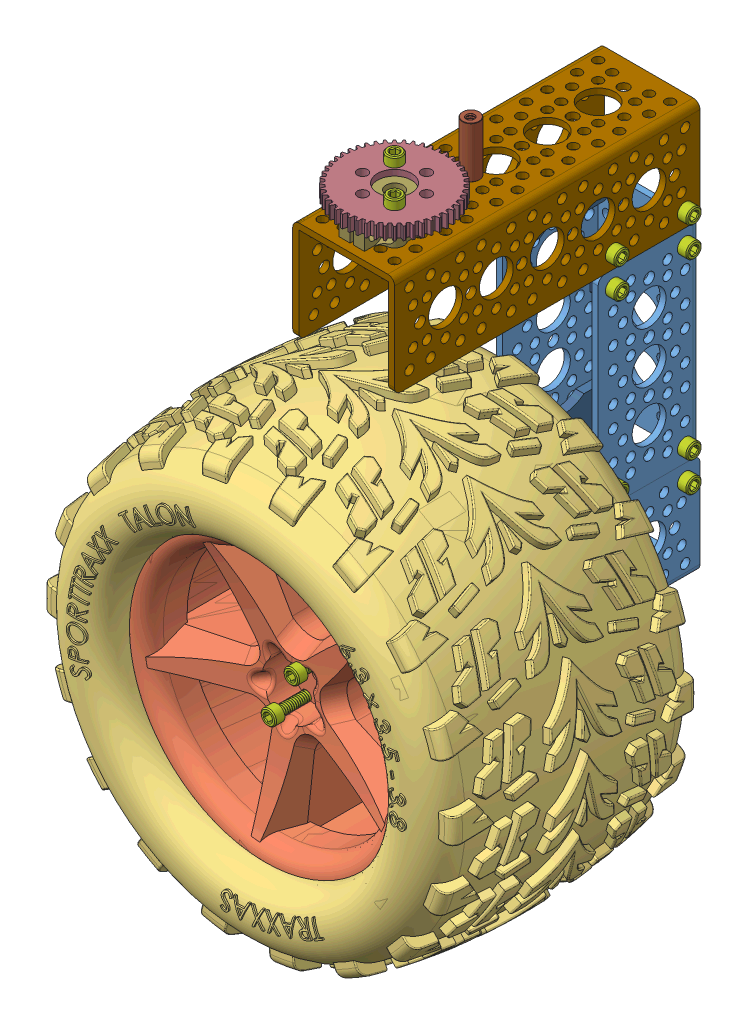
SolidWorks assembly Corner Wheel Assembly, configuration Default. Lengths in mm.
Overall size (182.86 244.12 157.75).
49 component instances, 13 part files, 84 mates.
Components (placement in the parent):
- Wheel Assembly-1: Wheel Assembly [Middle Wheel] at (53.3657 55.989 87.6081) size (182.86 183.23 157.75)
  - 3 Aluminum Channel-1: 3 Aluminum Channel [Default] at (-17.2943 26.284 30.6898) size (38.1 38.1 76.2)
  - Wheel-1: Wheel [Default] at (-70.1316 -42.318 140.7011) x (0 0 1) z (0.106642 0.994297 0) size (106.88 166.05 166.47)
    - Wheel Rim-1: Wheel Rim [Default] at (-5.7009 62.13 94.8184) size (78.74 101.6 101.6)
    - Wheel Tire-1: Wheel Tire [Default] at (-5.7009 62.1295 94.8183) size (106.88 166.05 166.47)
  - 25m Bore Side Tapped Clamping Mount-1: 25m Bore Side Tapped Clamping Mount [Default] at (1.1407 51.5007 106.1447) x (1 0 0) z (0 -1 0) size (33.76 11.43 64.42)
    - 25m Bore Side Tapped Clamping Mount-1: 25m Bore Side Tapped Clamping Mount [Default] at (0.615 -8.6446 6.1668) size (33.76 7.62 39.7)
    - #6-32 0_5 Bolt-1: #6-32 0_5 Bolt [Default] at (-31.135 -4.8346 -13.2719) x (0 0.2706 0.962692) z (-1 0 0) size (5.57 5.57 16.21)
  - 25mm Motor and Encoder-1: 25mm Motor and Encoder [Default] at (-28.8188 49.6309 104.1252) x (0.990268 -0.139173 0) z (0 0 1) size (25 32.85 80)
  - 6-32_SHCS-1: 6-32_SHCS [6-32 SHCS X .250] at (14.4557 58.8044 101.3102) x (0 0 -1) z (1 0 0) size (5.74 5.74 9.86)
  - 6-32_SHCS-2: 6-32_SHCS [6-32 SHCS X .250] at (-10.9443 58.8044 101.3102) x (0 0.924225 0.381849) z (-1 0 0) size (5.74 5.74 9.86)
  - 6-32_SHCS-3: 6-32_SHCS [6-32 SHCS X .250] at (-10.9443 31.8636 101.3102) x (0 0.924225 0.381849) z (-1 0 0) size (5.74 5.74 9.86)
  - 6-32_SHCS-4: 6-32_SHCS [6-32 SHCS X .250] at (14.4557 31.8636 101.3102) x (0 0 -1) z (1 0 0) size (5.74 5.74 9.86)
  - 6-32_SHCS-5: 6-32_SHCS [6-32 SHCS X 1.250] at (6.0479 54.1206 133.797) x (-0.106642 -0.994297 0) z (0 0 1) size (5.74 5.74 35.26)
  - 6-32_SHCS-6: 6-32_SHCS [6-32 SHCS X 1.250] at (-2.5366 36.5473 133.797) x (-0.106642 -0.994297 0) z (0 0 1) size (5.74 5.74 35.26)
  - 4mm Face Tapped Clamping Hub-1: 4mm Face Tapped Clamping Hub [Default] at (1.7557 45.334 125.4752) x (0.945719 0.324986 0) z (0.324986 -0.945719 0) size (20.57 9.64 26.29)
- 3 Aluminum Channel-1: 3 Aluminum Channel [Default] at (36.0714 196.573 118.2979) x (1 0 0) z (0 -1 0) size (38.1 38.1 76.2)
- 4.5 Aluminum channel-1: 4.5 Aluminum channel [Default] at (36.0714 234.673 232.5979) x (1 0 0) z (0 0 -1) size (38.1 38.1 114.3)
- Channel Connector-1: Channel Connector [Default] at (71.8854 120.373 137.3479) x (0 0 1) z (0 -1 0) size (33.29 3.38 17.51)
- Channel Connector-2: Channel Connector [Default] at (41.5324 120.373 137.3479) x (0 0 1) z (0 -1 0) size (33.29 3.38 17.51)
- Channel Connector-3: Channel Connector [Default] at (71.8854 196.573 137.3479) x (0 0 1) z (0 -1 0) size (33.29 3.38 17.51)
- Channel Connector-4: Channel Connector [Default] at (38.3574 196.573 137.3479) x (0 0 1) z (0 1 0) size (33.29 3.38 17.51)
- 6-32_SHCS-1: 6-32_SHCS [6-32 SHCS X .250] at (42.4214 114.7934 150.8183) x (0 0.924225 0.381849) z (-1 0 0) size (5.74 5.74 9.86)
- 6-32_SHCS-2: 6-32_SHCS [6-32 SHCS X .250] at (67.8214 114.7934 150.8183) x (0 0 -1) z (1 0 0) size (5.74 5.74 9.86)
- 6-32_SHCS-3: 6-32_SHCS [6-32 SHCS X .250] at (42.4214 114.7934 123.8776) x (0 0.924225 0.381849) z (-1 0 0) size (5.74 5.74 9.86)
- 6-32_SHCS-4: 6-32_SHCS [6-32 SHCS X .250] at (67.8214 114.7934 123.8776) x (0 0 -1) z (1 0 0) size (5.74 5.74 9.86)
- 6-32_SHCS-5: 6-32_SHCS [6-32 SHCS X .250] at (67.8214 125.9526 123.8776) x (0 -0.924225 -0.381849) z (1 0 0) size (5.74 5.74 9.86)
- 6-32_SHCS-6: 6-32_SHCS [6-32 SHCS X .250] at (42.4214 125.9526 123.8776) x (0 0 1) z (-1 0 0) size (5.74 5.74 9.86)
- 6-32_SHCS-7: 6-32_SHCS [6-32 SHCS X .250] at (42.4214 125.9526 150.8183) x (0 0.924225 0.381849) z (-1 0 0) size (5.74 5.74 9.86)
- 6-32_SHCS-8: 6-32_SHCS [6-32 SHCS X .250] at (67.8214 125.9526 150.8183) x (0 0 -1) z (1 0 0) size (5.74 5.74 9.86)
- 6-32_SHCS-9: 6-32_SHCS [6-32 SHCS X .250] at (42.4214 190.9934 150.8183) x (0 0.924225 0.381849) z (-1 0 0) size (5.74 5.74 9.86)
- 6-32_SHCS-10: 6-32_SHCS [6-32 SHCS X .250] at (67.8214 190.9934 150.8183) x (0 0 -1) z (1 0 0) size (5.74 5.74 9.86)
- 6-32_SHCS-11: 6-32_SHCS [6-32 SHCS X .250] at (42.4214 190.9934 123.8776) x (0 0.924225 0.381849) z (-1 0 0) size (5.74 5.74 9.86)
- 6-32_SHCS-12: 6-32_SHCS [6-32 SHCS X .250] at (67.8214 190.9934 123.8776) x (0 0 -1) z (1 0 0) size (5.74 5.74 9.86)
- 6-32_SHCS-13: 6-32_SHCS [6-32 SHCS X .250] at (42.4214 202.1526 150.8183) x (0 0.924225 0.381849) z (-1 0 0) size (5.74 5.74 9.86)
- 6-32_SHCS-14: 6-32_SHCS [6-32 SHCS X .250] at (67.8214 202.1526 150.8183) x (0 0 -1) z (1 0 0) size (5.74 5.74 9.86)
- 6-32_SHCS-15: 6-32_SHCS [6-32 SHCS X .250] at (42.4214 202.1526 123.8776) x (0 0.924225 0.381849) z (-1 0 0) size (5.74 5.74 9.86)
- 6-32_SHCS-16: 6-32_SHCS [6-32 SHCS X .250] at (67.8214 202.1526 123.8776) x (0 0 -1) z (1 0 0) size (5.74 5.74 9.86)
- 6-32_SHCS-17: 6-32_SHCS [6-32 SHCS X .375] at (62.0362 236.8955 220.4627) x (1 0 0) z (0 1 0) size (5.74 5.74 13.03)
- 6-32_SHCS-18: 6-32_SHCS [6-32 SHCS X .375] at (48.2066 241.912 220.4627) x (0.296364 0 -0.955075) z (0 -1 0) size (5.74 5.74 13.03)
- 6-32_SHCS-19: 6-32_SHCS [6-32 SHCS X .375] at (62.0362 241.912 206.6331) x (-0.850964 0 -0.525225) z (0 -1 0) size (5.74 5.74 13.03)
- 6-32_SHCS-20: 6-32_SHCS [6-32 SHCS X .375] at (48.2066 236.8955 206.6331) x (-0.379425 0 0.925222) z (0 1 0) size (5.74 5.74 13.03)
- 6-32_SHCS-21: 6-32_SHCS [6-32 SHCS X .375] at (55.1214 241.912 184.9729) x (-0.837169 0 -0.546944) z (0 -1 0) size (5.74 5.74 13.03)
- 6_32 standoff-1: 6_32 standoff [Default] at (55.1214 234.673 184.9729) x (0.654773 0 0.755826) z (-0.755826 0 0.654773) size (6.34 19.26 6.34)
- 0.25 Face Tapped Clamping Hub-1: 0.25 Face Tapped Clamping Hub [Default] at (55.1214 244.198 213.5479) x (1 0 0) z (0 0 -1) size (20.57 9.63 26.29)
- 48 Tooth 32 Pitch Gear-1: 48 Tooth 32 Pitch Gear [Default] at (55.1214 241.658 213.5479) x (0.965926 0 -0.258819) z (0.258819 0 0.965926) size (39.7 4.76 39.7)
- Wheel-1: Wheel [Default] at (-16.766 13.671 228.3093) x (0 0 1) z (0.106642 0.994297 0) size (106.88 166.05 166.47)
  - Wheel Rim-1: Wheel Rim [Default] at (-5.7009 62.13 94.8184) size (78.74 101.6 101.6)
  - Wheel Tire-1: Wheel Tire [Default] at (-5.7009 62.1295 94.8183) size (106.88 166.05 166.47)
Mates (geometry in assembly coordinates):
- Coincident1: coincident anti-aligned: plane of Wheel Assembly-1/3 Aluminum Channel-1 through (36.0714 120.373 194.4979) normal (0 1 0); plane of 3 Aluminum Channel-1 through (36.0714 120.373 118.2979) normal (0 -1 0)
- Concentric1: concentric anti-aligned: cylinder of Wheel Assembly-1/3 Aluminum Channel-1 through (74.1714 114.7934 123.8776) axis (1 0 0) radius 1.778; cylinder of Channel Connector-2 through (38.3574 114.7934 123.8776) axis (-1 0 0) radius 1.3526
- Concentric2: concentric anti-aligned: cylinder of Wheel Assembly-1/3 Aluminum Channel-1 through (74.1714 114.7934 123.8776) axis (1 0 0) radius 1.778; cylinder of Channel Connector-1 through (68.7104 114.7934 123.8776) axis (-1 0 0) radius 1.3526
- Concentric3: concentric anti-aligned: cylinder of Wheel Assembly-1/3 Aluminum Channel-1 through (74.1714 114.7934 123.8776) axis (1 0 0) radius 1.778; cylinder of 6-32_SHCS-4 through (86.8714 114.7934 123.8776) axis (-1 0 0) radius 2.8702
- Concentric4: concentric aligned: cylinder of Wheel Assembly-1/3 Aluminum Channel-1 through (74.1714 114.7934 123.8776) axis (1 0 0) radius 1.778; cylinder of 6-32_SHCS-3 through (23.3714 114.7934 123.8776) axis (1 0 0) radius 2.8702
- Concentric5: concentric anti-aligned: cylinder of Wheel Assembly-1/3 Aluminum Channel-1 through (74.1714 114.7934 150.8183) axis (1 0 0) radius 1.778; cylinder of Channel Connector-2 through (38.3574 114.7934 150.8183) axis (-1 0 0) radius 1.3526
- Concentric6: concentric anti-aligned: cylinder of Wheel Assembly-1/3 Aluminum Channel-1 through (74.1714 114.7934 150.8183) axis (1 0 0) radius 1.778; cylinder of Channel Connector-1 through (68.7104 114.7934 150.8183) axis (-1 0 0) radius 1.3526
- Concentric7: concentric anti-aligned: cylinder of Wheel Assembly-1/3 Aluminum Channel-1 through (74.1714 114.7934 150.8183) axis (1 0 0) radius 1.778; cylinder of 6-32_SHCS-2 through (86.8714 114.7934 150.8183) axis (-1 0 0) radius 2.8702
- Concentric8: concentric aligned: cylinder of Wheel Assembly-1/3 Aluminum Channel-1 through (74.1714 114.7934 150.8183) axis (1 0 0) radius 1.778; cylinder of 6-32_SHCS-1 through (23.3714 114.7934 150.8183) axis (1 0 0) radius 2.8702
- Concentric9: concentric anti-aligned: cylinder of 3 Aluminum Channel-1 through (74.1714 125.9526 150.8183) axis (1 0 0) radius 1.778; cylinder of 6-32_SHCS-8 through (86.8714 125.9526 150.8183) axis (-1 0 0) radius 2.8702
- Concentric10: concentric aligned: cylinder of 3 Aluminum Channel-1 through (74.1714 125.9526 150.8183) axis (1 0 0) radius 1.778; cylinder of 6-32_SHCS-7 through (23.3714 125.9526 150.8183) axis (1 0 0) radius 2.8702
- Concentric11: concentric anti-aligned: cylinder of Channel Connector-1 through (68.7104 125.9526 123.8776) axis (-1 0 0) radius 1.3526; cylinder of 3 Aluminum Channel-1 through (74.1714 125.9526 123.8776) axis (1 0 0) radius 1.778
- Concentric12: concentric aligned: cylinder of Channel Connector-1 through (68.7104 125.9526 123.8776) axis (-1 0 0) radius 1.3526; cylinder of Channel Connector-2 through (38.3574 125.9526 123.8776) axis (-1 0 0) radius 1.3526
- Concentric13: concentric anti-aligned: cylinder of Channel Connector-1 through (68.7104 125.9526 123.8776) axis (-1 0 0) radius 1.3526; cylinder of 6-32_SHCS-6 through (23.3714 125.9526 123.8776) axis (1 0 0) radius 2.8702
- Concentric14: concentric aligned: cylinder of Channel Connector-1 through (68.7104 125.9526 123.8776) axis (-1 0 0) radius 1.3526; cylinder of 6-32_SHCS-5 through (86.8714 125.9526 123.8776) axis (-1 0 0) radius 2.8702
- Concentric15: concentric aligned: cylinder of 3 Aluminum Channel-1 through (74.1714 190.9934 123.8776) axis (1 0 0) radius 1.778; cylinder of Channel Connector-4 through (41.5324 190.9934 123.8776) axis (1 0 0) radius 1.3526
- Concentric16: concentric anti-aligned: cylinder of 3 Aluminum Channel-1 through (74.1714 190.9934 123.8776) axis (1 0 0) radius 1.778; cylinder of Channel Connector-3 through (68.7104 190.9934 123.8776) axis (-1 0 0) radius 1.3526
- Concentric17: concentric anti-aligned: cylinder of 3 Aluminum Channel-1 through (74.1714 190.9934 123.8776) axis (1 0 0) radius 1.778; cylinder of 6-32_SHCS-12 through (86.8714 190.9934 123.8776) axis (-1 0 0) radius 2.8702
- Concentric18: concentric aligned: cylinder of 3 Aluminum Channel-1 through (74.1714 190.9934 123.8776) axis (1 0 0) radius 1.778; cylinder of 6-32_SHCS-11 through (23.3714 190.9934 123.8776) axis (1 0 0) radius 2.8702
- Concentric19: concentric aligned: cylinder of 3 Aluminum Channel-1 through (74.1714 190.9934 150.8183) axis (1 0 0) radius 1.778; cylinder of Channel Connector-4 through (41.5324 190.9934 150.8183) axis (1 0 0) radius 1.3526
- Concentric20: concentric anti-aligned: cylinder of 3 Aluminum Channel-1 through (74.1714 190.9934 150.8183) axis (1 0 0) radius 1.778; cylinder of Channel Connector-3 through (68.7104 190.9934 150.8183) axis (-1 0 0) radius 1.3526
- Concentric21: concentric anti-aligned: cylinder of 3 Aluminum Channel-1 through (74.1714 190.9934 150.8183) axis (1 0 0) radius 1.778; cylinder of 6-32_SHCS-10 through (86.8714 190.9934 150.8183) axis (-1 0 0) radius 2.8702
- Concentric22: concentric aligned: cylinder of 3 Aluminum Channel-1 through (74.1714 190.9934 150.8183) axis (1 0 0) radius 1.778; cylinder of 6-32_SHCS-9 through (23.3714 190.9934 150.8183) axis (1 0 0) radius 2.8702
- Concentric23: concentric aligned: cylinder of Channel Connector-4 through (41.5324 202.1526 123.8776) axis (1 0 0) radius 1.3526; cylinder of 4.5 Aluminum channel-1 through (74.1714 202.1526 123.8776) axis (1 0 0) radius 1.778
- Concentric24: concentric anti-aligned: cylinder of Channel Connector-4 through (41.5324 202.1526 123.8776) axis (1 0 0) radius 1.3526; cylinder of 6-32_SHCS-16 through (86.8714 202.1526 123.8776) axis (-1 0 0) radius 2.8702
- Concentric25: concentric aligned: cylinder of Channel Connector-4 through (41.5324 202.1526 123.8776) axis (1 0 0) radius 1.3526; cylinder of 6-32_SHCS-15 through (23.3714 202.1526 123.8776) axis (1 0 0) radius 2.8702
- Concentric26: concentric aligned: cylinder of Channel Connector-4 through (41.5324 202.1526 150.8183) axis (1 0 0) radius 1.3526; cylinder of 4.5 Aluminum channel-1 through (74.1714 202.1526 150.8183) axis (1 0 0) radius 1.778
- Concentric27: concentric anti-aligned: cylinder of Channel Connector-4 through (41.5324 202.1526 150.8183) axis (1 0 0) radius 1.3526; cylinder of 6-32_SHCS-14 through (86.8714 202.1526 150.8183) axis (-1 0 0) radius 2.8702
- Concentric28: concentric aligned: cylinder of Channel Connector-4 through (41.5324 202.1526 150.8183) axis (1 0 0) radius 1.3526; cylinder of 6-32_SHCS-13 through (23.3714 202.1526 150.8183) axis (1 0 0) radius 2.8702
- Coincident2: coincident aligned: plane of Wheel Assembly-1/3 Aluminum Channel-1 through (36.0714 82.273 194.4979) normal (-1 0 0); plane of 3 Aluminum Channel-1 through (36.0714 120.373 118.2979) normal (-1 0 0)
- Coincident3: coincident aligned: plane of Wheel Assembly-1/3 Aluminum Channel-1 through (36.0714 82.273 194.4979) normal (-1 0 0); plane of 4.5 Aluminum channel-1 through (36.0714 234.673 118.2979) normal (-1 0 0)
- Coincident4: coincident anti-aligned: plane of Wheel Assembly-1/3 Aluminum Channel-1 through (36.0714 82.273 194.4979) normal (-1 0 0); plane of 6-32_SHCS-13 through (36.0714 202.1526 150.8183) normal (1 0 0)
- Coincident5: coincident anti-aligned: plane of Wheel Assembly-1/3 Aluminum Channel-1 through (36.0714 82.273 194.4979) normal (-1 0 0); plane of 6-32_SHCS-9 through (36.0714 190.9934 150.8183) normal (1 0 0)
- Coincident6: coincident anti-aligned: plane of Wheel Assembly-1/3 Aluminum Channel-1 through (36.0714 82.273 194.4979) normal (-1 0 0); plane of 6-32_SHCS-11 through (36.0714 190.9934 123.8776) normal (1 0 0)
- Coincident7: coincident anti-aligned: plane of Wheel Assembly-1/3 Aluminum Channel-1 through (36.0714 82.273 194.4979) normal (-1 0 0); plane of 6-32_SHCS-15 through (36.0714 202.1526 123.8776) normal (1 0 0)
- Coincident8: coincident anti-aligned: plane of Wheel Assembly-1/3 Aluminum Channel-1 through (36.0714 82.273 194.4979) normal (-1 0 0); plane of 6-32_SHCS-1 through (36.0714 114.7934 150.8183) normal (1 0 0)
- Coincident9: coincident anti-aligned: plane of Wheel Assembly-1/3 Aluminum Channel-1 through (36.0714 82.273 194.4979) normal (-1 0 0); plane of 6-32_SHCS-7 through (36.0714 125.9526 150.8183) normal (1 0 0)
- Coincident10: coincident anti-aligned: plane of Wheel Assembly-1/3 Aluminum Channel-1 through (36.0714 82.273 194.4979) normal (-1 0 0); plane of 6-32_SHCS-6 through (36.0714 125.9526 123.8776) normal (1 0 0)
- Coincident11: coincident anti-aligned: plane of Wheel Assembly-1/3 Aluminum Channel-1 through (36.0714 82.273 194.4979) normal (-1 0 0); plane of 6-32_SHCS-3 through (36.0714 114.7934 123.8776) normal (1 0 0)
- Coincident12: coincident anti-aligned: plane of Wheel Assembly-1/3 Aluminum Channel-1 through (74.1714 120.373 194.4979) normal (1 0 0); plane of 6-32_SHCS-5 through (74.1714 125.9526 123.8776) normal (-1 0 0)
- Coincident13: coincident anti-aligned: plane of Wheel Assembly-1/3 Aluminum Channel-1 through (74.1714 120.373 194.4979) normal (1 0 0); plane of 6-32_SHCS-4 through (74.1714 114.7934 123.8776) normal (-1 0 0)
- Coincident14: coincident anti-aligned: plane of Wheel Assembly-1/3 Aluminum Channel-1 through (74.1714 120.373 194.4979) normal (1 0 0); plane of 6-32_SHCS-8 through (74.1714 125.9526 150.8183) normal (-1 0 0)
- Coincident15: coincident anti-aligned: plane of Wheel Assembly-1/3 Aluminum Channel-1 through (74.1714 120.373 194.4979) normal (1 0 0); plane of 6-32_SHCS-2 through (74.1714 114.7934 150.8183) normal (-1 0 0)
- Coincident16: coincident anti-aligned: plane of Wheel Assembly-1/3 Aluminum Channel-1 through (74.1714 120.373 194.4979) normal (1 0 0); plane of 6-32_SHCS-16 through (74.1714 202.1526 123.8776) normal (-1 0 0)
- Coincident17: coincident anti-aligned: plane of Wheel Assembly-1/3 Aluminum Channel-1 through (74.1714 120.373 194.4979) normal (1 0 0); plane of 6-32_SHCS-14 through (74.1714 202.1526 150.8183) normal (-1 0 0)
- Coincident18: coincident anti-aligned: plane of Wheel Assembly-1/3 Aluminum Channel-1 through (74.1714 120.373 194.4979) normal (1 0 0); plane of 6-32_SHCS-10 through (74.1714 190.9934 150.8183) normal (-1 0 0)
- Coincident19: coincident anti-aligned: plane of Wheel Assembly-1/3 Aluminum Channel-1 through (74.1714 120.373 194.4979) normal (1 0 0); plane of 6-32_SHCS-12 through (74.1714 190.9934 123.8776) normal (-1 0 0)
- Coincident20: coincident anti-aligned: plane of 4.5 Aluminum channel-1 through (71.8854 232.387 118.2979) normal (-1 0 0); plane of Channel Connector-3 through (71.8854 196.573 137.3479) normal (1 0 0)
- Coincident21: coincident anti-aligned: plane of 4.5 Aluminum channel-1 through (71.8854 232.387 118.2979) normal (-1 0 0); plane of Channel Connector-1 through (71.8854 120.373 137.3479) normal (1 0 0)
- Coincident22: coincident anti-aligned: plane of Wheel Assembly-1/3 Aluminum Channel-1 through (38.3574 120.373 194.4979) normal (1 0 0); plane of Channel Connector-2 through (38.3574 120.373 137.3479) normal (-1 0 0)
- Coincident23: coincident anti-aligned: plane of Wheel Assembly-1/3 Aluminum Channel-1 through (38.3574 120.373 194.4979) normal (1 0 0); plane of Channel Connector-4 through (38.3574 196.573 137.3479) normal (-1 0 0)
- Coincident24: coincident anti-aligned: plane of 4.5 Aluminum channel-1 through (74.1714 234.673 118.2979) normal (0 1 0); plane of 0.25 Face Tapped Clamping Hub-1 through (55.1214 234.673 213.5479) normal (0 -1 0)
- Concentric29: concentric anti-aligned: cylinder of 0.25 Face Tapped Clamping Hub-1 through (55.1214 241.658 213.5479) axis (0 1 0) radius 6.35; cylinder of 48 Tooth 32 Pitch Gear-1 through (55.1214 246.4205 213.5479) axis (0 -1 0) radius 6.35
- Concentric30: concentric aligned: cylinder of 0.25 Face Tapped Clamping Hub-1 through (55.1214 241.658 213.5479) axis (0 1 0) radius 6.35; cylinder of 4.5 Aluminum channel-1 through (55.1214 234.673 213.5479) axis (0 1 0) radius 6.3627
- Concentric31: concentric anti-aligned: cylinder of 0.25 Face Tapped Clamping Hub-1 through (48.2066 234.673 220.4627) axis (0 -1 0) radius 1.3526; cylinder of 4.5 Aluminum channel-1 through (48.2066 234.673 220.4627) axis (0 1 0) radius 1.778
- Concentric32: concentric anti-aligned: cylinder of 0.25 Face Tapped Clamping Hub-1 through (48.2066 234.673 220.4627) axis (0 -1 0) radius 1.3526; cylinder of 6-32_SHCS-18 through (48.2066 219.687 220.4627) axis (0 1 0) radius 2.8702
- Concentric33: concentric anti-aligned: cylinder of 0.25 Face Tapped Clamping Hub-1 through (62.0362 234.673 206.6331) axis (0 -1 0) radius 1.3526; cylinder of 6-32_SHCS-19 through (62.0362 219.687 206.6331) axis (0 1 0) radius 2.8702
- Concentric34: concentric anti-aligned: cylinder of 0.25 Face Tapped Clamping Hub-1 through (62.0362 234.673 206.6331) axis (0 -1 0) radius 1.3526; cylinder of 4.5 Aluminum channel-1 through (62.0362 234.673 206.6331) axis (0 1 0) radius 1.778
- Concentric35: concentric anti-aligned: cylinder of 48 Tooth 32 Pitch Gear-1 through (62.0362 246.4205 220.4627) axis (0 1 0) radius 1.8986; cylinder of 0.25 Face Tapped Clamping Hub-1 through (62.0362 234.673 220.4627) axis (0 -1 0) radius 1.3526
- Concentric36: concentric anti-aligned: cylinder of 48 Tooth 32 Pitch Gear-1 through (62.0362 246.4205 220.4627) axis (0 1 0) radius 1.8986; cylinder of 6-32_SHCS-17 through (62.0362 259.1205 220.4627) axis (0 -1 0) radius 2.8702
- Concentric37: concentric anti-aligned: cylinder of 48 Tooth 32 Pitch Gear-1 through (48.2066 246.4205 206.6331) axis (0 1 0) radius 1.8986; cylinder of 0.25 Face Tapped Clamping Hub-1 through (48.2066 234.673 206.6331) axis (0 -1 0) radius 1.3526
- Concentric38: concentric anti-aligned: cylinder of 48 Tooth 32 Pitch Gear-1 through (48.2066 246.4205 206.6331) axis (0 1 0) radius 1.8986; cylinder of 6-32_SHCS-20 through (48.2066 259.1205 206.6331) axis (0 -1 0) radius 2.8702
- Coincident25: coincident anti-aligned: plane of 6-32_SHCS-20 through (48.2066 246.4205 206.6331) normal (0 -1 0); plane of 48 Tooth 32 Pitch Gear-1 through (55.1214 246.4205 213.5479) normal (0 1 0)
- Coincident26: coincident aligned: plane of 6-32_SHCS-20 through (48.2066 246.4205 206.6331) normal (0 -1 0); plane of 6-32_SHCS-17 through (62.0362 246.4205 220.4627) normal (0 -1 0)
- Coincident27: coincident anti-aligned: plane of 4.5 Aluminum channel-1 through (38.3574 232.387 118.2979) normal (0 -1 0); plane of 6-32_SHCS-19 through (62.0362 232.387 206.6331) normal (0 1 0)
- Coincident28: coincident anti-aligned: plane of 4.5 Aluminum channel-1 through (38.3574 232.387 118.2979) normal (0 -1 0); plane of 6-32_SHCS-18 through (48.2066 232.387 220.4627) normal (0 1 0)
- Coincident29: coincident anti-aligned: plane of 0.25 Face Tapped Clamping Hub-1 through (55.1214 241.658 213.5479) normal (0 1 0); plane of 48 Tooth 32 Pitch Gear-1 through (55.1214 241.658 213.5479) normal (0 -1 0)
- Concentric39: concentric aligned: cylinder of 6-32_SHCS-21 through (55.1214 219.687 184.9729) axis (0 1 0) radius 2.8702; cylinder of 4.5 Aluminum channel-1 through (55.1214 234.673 184.9729) axis (0 1 0) radius 2.032
- Coincident31: coincident anti-aligned: plane of 4.5 Aluminum channel-1 through (38.3574 232.387 118.2979) normal (0 -1 0); plane of 6-32_SHCS-21 through (55.1214 232.387 184.9729) normal (0 1 0)
- Concentric41: concentric anti-aligned: cylinder of 4.5 Aluminum channel-1 through (55.1214 234.673 184.9729) axis (0 1 0) radius 2.032; cylinder of 6_32 standoff-1 through (55.1214 253.723 184.9729) axis (0 -1 0) radius 3.1712
- Coincident32: coincident anti-aligned: plane of 4.5 Aluminum channel-1 through (74.1714 234.673 118.2979) normal (0 1 0); plane of 6_32 standoff-1 through (55.1214 234.673 184.9729) normal (0 -1 0)
- Concentric45: concentric aligned: cylinder of 6-32_SHCS-11 through (23.3714 190.9934 123.8776) axis (1 0 0) radius 2.8702; cylinder of Channel Connector-4 through (41.5324 190.9934 123.8776) axis (1 0 0) radius 1.3526
- Concentric46: concentric anti-aligned: cylinder of 6-32_SHCS-11 through (23.3714 190.9934 123.8776) axis (1 0 0) radius 2.8702; cylinder of 6-32_SHCS-12 through (86.8714 190.9934 123.8776) axis (-1 0 0) radius 2.8702
- Concentric47: concentric anti-aligned: cylinder of 6-32_SHCS-9 through (23.3714 190.9934 150.8183) axis (1 0 0) radius 2.8702; cylinder of 6-32_SHCS-10 through (86.8714 190.9934 150.8183) axis (-1 0 0) radius 2.8702
- Concentric52: concentric anti-aligned: cylinder of 6-32_SHCS-1 through (23.3714 114.7934 150.8183) axis (1 0 0) radius 2.8702; cylinder of Channel Connector-2 through (38.3574 114.7934 150.8183) axis (-1 0 0) radius 1.3526
- Concentric53: concentric anti-aligned: cylinder of 6-32_SHCS-1 through (23.3714 114.7934 150.8183) axis (1 0 0) radius 2.8702; cylinder of 6-32_SHCS-2 through (86.8714 114.7934 150.8183) axis (-1 0 0) radius 2.8702
- Coincident45: coincident anti-aligned: plane of 4.5 Aluminum channel-1 through (38.3574 196.573 118.2979) normal (1 0 0); plane of Channel Connector-4 through (38.3574 196.573 137.3479) normal (-1 0 0)
- Coincident46: coincident anti-aligned: plane of 4.5 Aluminum channel-1 through (38.3574 196.573 118.2979) normal (1 0 0); plane of Channel Connector-2 through (38.3574 120.373 137.3479) normal (-1 0 0)
- Concentric54: concentric aligned: cylinder of Wheel Assembly-1/6-32_SHCS-5 through (59.4136 110.1097 265.8551) axis (0 0 -1) radius 2.8702; cylinder of Wheel-1/Wheel Rim-1 through (59.4136 110.1097 261.9783) axis (0 0 -1) radius 1.905
- Concentric55: concentric aligned: cylinder of Wheel Assembly-1/6-32_SHCS-6 through (50.8291 92.5363 265.8551) axis (0 0 -1) radius 2.8702; cylinder of Wheel-1/Wheel Rim-1 through (50.8291 92.5363 261.9783) axis (0 0 -1) radius 1.905
- Tangent1: tangent: plane of Wheel Assembly-1/4mm Face Tapped Clamping Hub-1 through (55.1214 101.323 222.6083) normal (0 0 1); face of Wheel-1/Wheel Rim-1
- Concentric63: concentric aligned: cylinder of Channel Connector-3 through (68.7104 202.1526 123.8776) axis (-1 0 0) radius 1.3526; cylinder of 6-32_SHCS-16 through (86.8714 202.1526 123.8776) axis (-1 0 0) radius 2.8702
- Concentric64: concentric aligned: cylinder of Channel Connector-3 through (68.7104 202.1526 150.8183) axis (-1 0 0) radius 1.3526; cylinder of 6-32_SHCS-14 through (86.8714 202.1526 150.8183) axis (-1 0 0) radius 2.8702
- Concentric65: concentric aligned: cylinder of Channel Connector-1 through (68.7104 114.7934 123.8776) axis (-1 0 0) radius 1.3526; cylinder of 6-32_SHCS-4 through (86.8714 114.7934 123.8776) axis (-1 0 0) radius 2.8702
